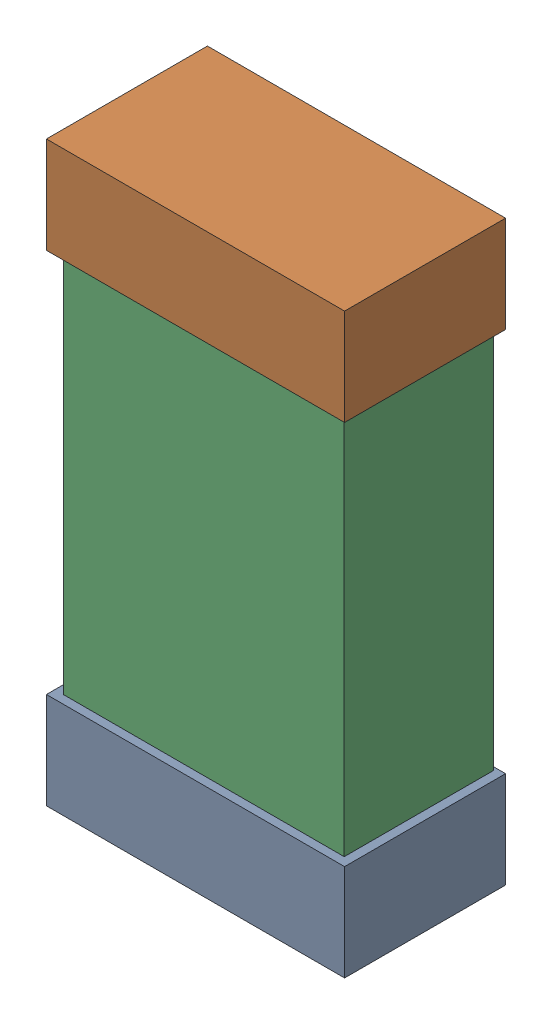
SolidWorks assembly C35, configuration Default. Lengths in mm.
Overall size (0.85 1.65 0.46).
6 component instances, 2 part files, 0 mates.
Components (placement in the parent):
- 432138512_52-1: 432138512_52 [Default] at (19.3102 57.8813 -0.8715) size (0.85 0.28 0.46)
  - Extruded-1: Extruded [Default] at origin size (0.85 0.28 0.46)
- 432138512_53-1: 432138512_53 [Default] at (19.3102 59.2528 -0.8715) size (0.85 0.28 0.46)
  - Extruded-1: Extruded [Default] at origin size (0.85 0.28 0.46)
- 432124816_26-1: 432124816_26 [Default] at (19.3102 58.567 -0.8615) size (0.8 1.5 0.42)
  - Extruded (1)-1: Extruded (1) [Default] at origin size (0.8 1.5 0.42)
